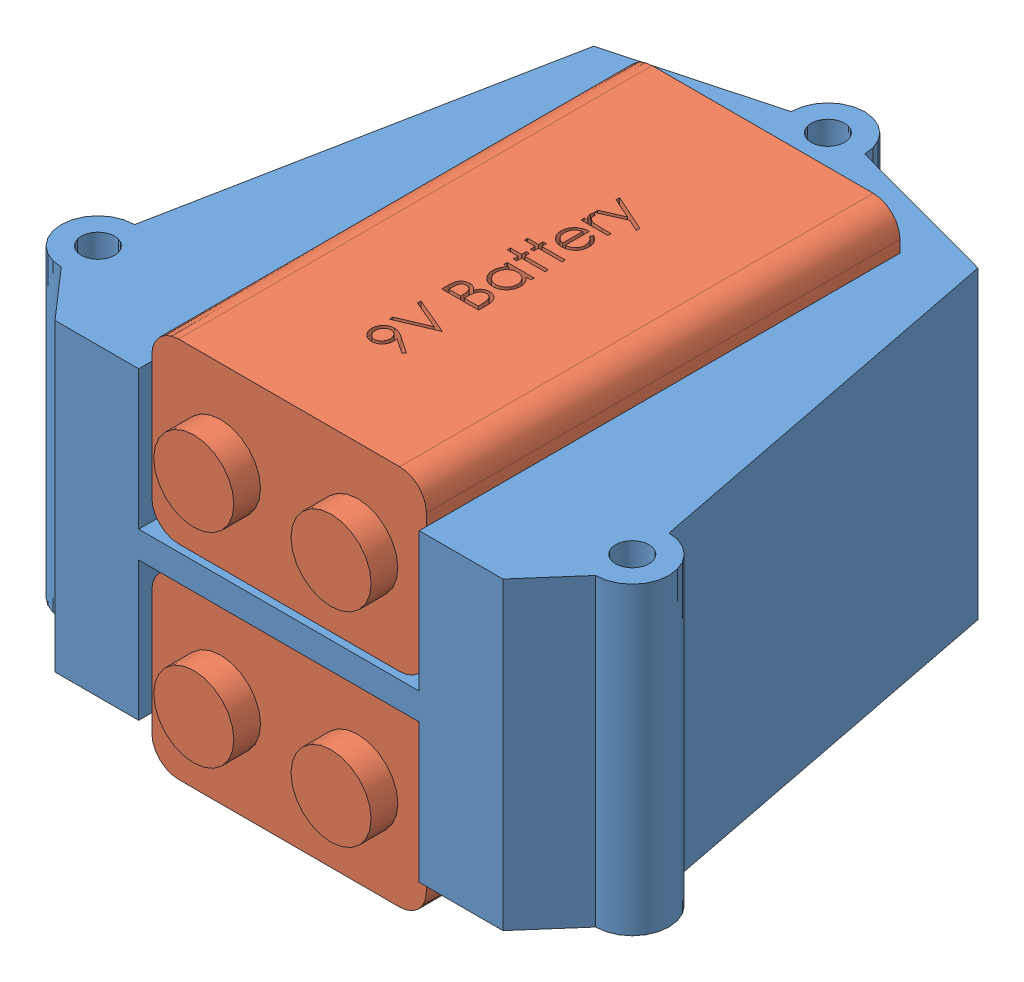
SolidWorks assembly S1B_Sensor_Power_Stack_Assy, configuration Default. Lengths in mm.
Overall size (57.8 36.27 57.54).
3 component instances, 2 part files, 6 mates.
Components (placement in the parent):
- S1B_Sensor_Power_Stack-1: S1B_Sensor_Power_Stack [Default] at (24.3714 13.7485 42.0133) size (57.8 28.96 55.69)
- S1B_9V Battery-1: S1B_9V Battery [Default] at (37.7064 32.0365 66.7275) x (0 0 -1) z (1 0 0) size (47.57 16.87 26.11)
- S1B_9V Battery-2: S1B_9V Battery [Default] at (37.7064 12.6309 66.7275) x (0 0 -1) z (1 0 0) size (47.57 16.87 26.11)
Mates (geometry in assembly coordinates):
- Coincident1: coincident aligned: plane of 9V Battery-1 through (37.7064 48.9021 19.1533) normal (0 0 -1); plane of 9V Battery-2 through (37.7064 29.4965 19.1533) normal (0 0 -1)
- Coincident2: coincident anti-aligned: plane of S1B_Sensor_Power_Stack-1 through (24.3714 13.7485 19.1533) normal (0 0 1); plane of 9V Battery-1 through (37.7064 48.9021 19.1533) normal (0 0 -1)
- Coincident3: coincident anti-aligned: plane of S1B_Sensor_Power_Stack-1 through (37.7064 32.0365 19.1533) normal (0 1 0); plane of 9V Battery-1 through (37.7064 32.0365 66.7275) normal (0 -1 0)
- Coincident4: coincident anti-aligned: plane of S1B_Sensor_Power_Stack-1 through (37.7064 49.8165 19.1533) normal (-1 0 0); plane of 9V Battery-1 through (37.7064 48.9021 66.7275) normal (1 0 0)
- Coincident5: coincident anti-aligned: plane of S1B_Sensor_Power_Stack-1 through (37.7064 11.7165 19.1533) normal (-1 0 0); plane of 9V Battery-2 through (37.7064 29.4965 66.7275) normal (1 0 0)
- Coincident6: coincident anti-aligned: plane of S1B_Sensor_Power_Stack-1 through (37.7064 29.4965 19.1533) normal (0 -1 0); plane of 9V Battery-2 through (37.7064 29.4965 66.7275) normal (0 1 0)
